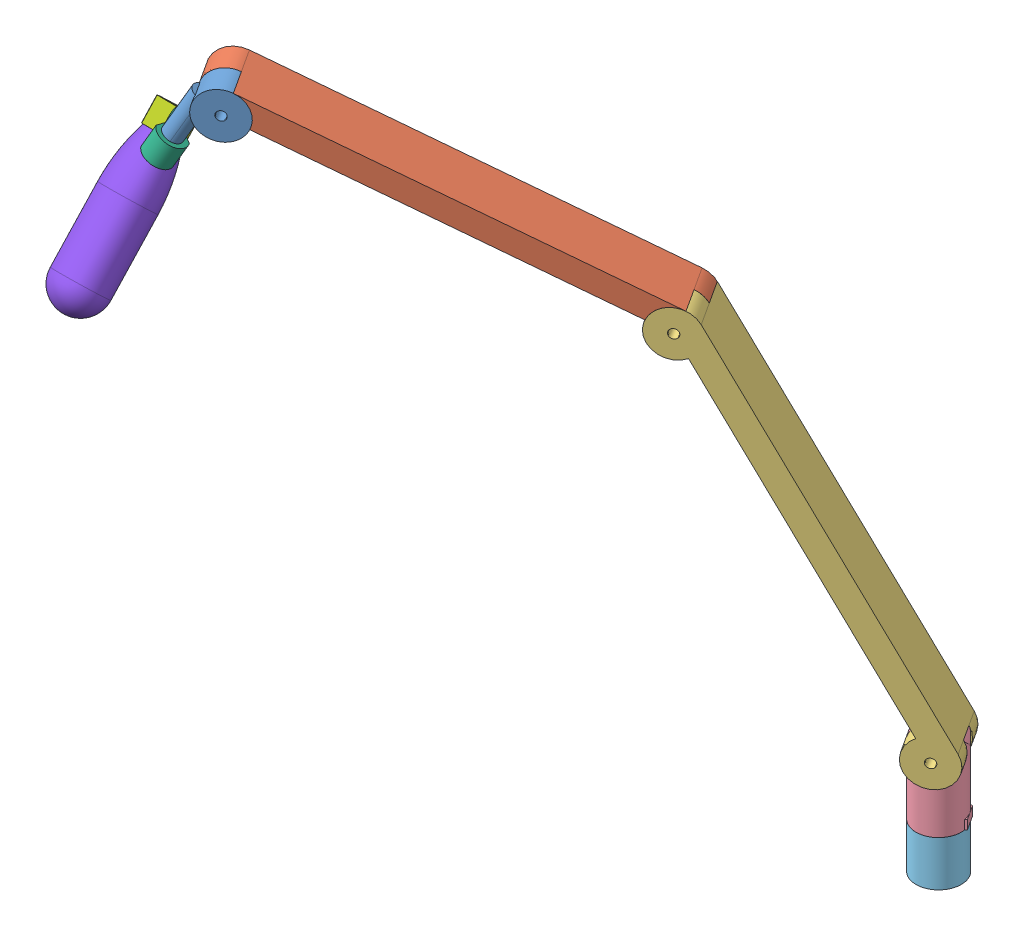
SolidWorks assembly Mic-Halter, configuration Standard. Lengths in mm.
Overall size (630.43 695.4 486.89).
8 component instances, 8 part files, 21 mates.
Components (placement in the parent):
- Mic-Arm-Kopf-1: Mic-Arm-Kopf [Standard] at (-467.7674 659.0081 383.0771) x (-0.405998 -0.875271 0.262803) z (-0.543395 0 -0.839477) size (75 55 30)
- Mic-Arm-Oberarm-1: Mic-Arm-Oberarm [Standard] at (-484.0692 659.0081 357.8928) x (-0.771647 0.393791 0.499489) z (-0.543395 0 -0.839477) size (443 50 60)
- Mic-Arm-Unterarm-1: Mic-Arm-Unterarm [Standard] at (-180.8117 504.2484 161.5937) x (-0.398411 0.880205 0.257892) z (-0.543395 0 -0.839477) size (482 50 60)
- Mic-Arm-Fuß-1: Mic-Arm-Fuß [Standard] at (-8.6981 124 50.1843) x (0 -1 0) z (-0.543395 0 -0.839477) size (99 50 50)
- Mic-Arm-Fuß-Boden-1: Mic-Arm-Fuß-Boden [Standard] at (-25 0 25) x (0 1 0) z (1 0 0) size (50 50 50)
- Mic-P120-Halter-Stativ-1: Mic-P120-Halter-Stativ [Standard] at (-527.2154 624.9172 367.9532) x (-0.579665 0.024326 -0.814492) z (-0.405998 -0.875271 0.262803) size (57.5 30 25)
- Mic-P12-Halter-Mic-1: Mic-P12-Halter-Mic [Standard] at (-574.0997 601.5346 315.0385) x (0.707701 0.484338 0.51437) z (0.002068 -0.729458 0.684022) size (71.5 38 25)
- Mic-P120-1: Mic-P120 [Standard] at (-574.048 583.2982 332.139) x (-0.877164 -0.329783 -0.349037) z (-0.480187 0.599278 0.640536) size (54 160 54)
Mates (geometry in assembly coordinates):
- Deckungsgleich1: coincident anti-aligned: plane of Mic-Arm-Oberarm-1 through (-500.3711 659.0081 332.7085) normal (0.543395 0 0.839477); plane of Mic-Arm-Kopf-1 through (-500.3711 659.0081 332.7085) normal (-0.543395 0 -0.839477)
- Konzentrisch1: concentric aligned: cylinder of Mic-Arm-Oberarm-1 through (-516.6729 659.0081 307.5242) axis (0.543395 0 0.839477) radius 5; cylinder of Mic-Arm-Kopf-1 through (-500.3711 659.0081 332.7085) axis (0.543395 0 0.839477) radius 5
- Deckungsgleich2: coincident anti-aligned: plane of Mic-Arm-Oberarm-1 through (-197.1136 504.2484 136.4094) normal (0.543395 0 0.839477); plane of Mic-Arm-Unterarm-1 through (-197.1136 504.2484 136.4094) normal (-0.543395 0 -0.839477)
- Konzentrisch2: concentric aligned: cylinder of Mic-Arm-Oberarm-1 through (-213.4154 504.2484 111.2251) axis (0.543395 0 0.839477) radius 5; cylinder of Mic-Arm-Unterarm-1 through (-213.4154 504.2484 111.2251) axis (0.543395 0 0.839477) radius 5
- Konzentrisch3: concentric aligned: cylinder of Mic-Arm-Unterarm-1 through (-41.3019 124 -0.1843) axis (0.543395 0 0.839477) radius 5; cylinder of Mic-Arm-Fuß-1 through (-41.3019 124 -0.1843) axis (0.543395 0 0.839477) radius 5
- Deckungsgleich7: coincident anti-aligned: plane of Mic-Arm-Fuß-Boden-1 through (-25 0 25) normal (0 -1 0); plane of assembly through (0 0 0) normal (0 1 0)
- Deckungsgleich8: coincident anti-aligned: plane of Mic-Arm-Fuß-Boden-1 through (-15 40 0) normal (0 0 -1); plane of assembly through (0 0 0) normal (0 0 1)
- Tangential1: tangent aligned: cylinder of Mic-Arm-Fuß-Boden-1 through (-25 50 25) axis (0 -1 0) radius 25; plane of assembly through (0 0 0) normal (1 0 0)
- Deckungsgleich9: coincident aligned: line of Mic-Arm-Fuß-1 through (-25 134 25) axis (0 -1 0); line of Mic-Arm-Fuß-Boden-1 through (-25 50 25) axis (0 -1 0)
- Deckungsgleich10: coincident anti-aligned: plane of Mic-Arm-Fuß-1 through (-62.2888 50 13.4006) normal (0 -1 0); plane of Mic-Arm-Fuß-Boden-1 through (-25 50 25) normal (0 1 0)
- LimitWinkel1: limit planar angle = 4.137913 rad anti-aligned: plane of Mic-Arm-Fuß-Boden-1 through (-15 40 0) normal (0 0 -1); plane of Mic-Arm-Fuß-1 through (1.4209 60 19.8099) normal (0.839477 0 -0.543395)
- Deckungsgleich12: coincident anti-aligned: plane of Mic-Arm-Unterarm-1 through (-30.434 124 16.6052) normal (0.543395 0 0.839477); plane of Mic-Arm-Fuß-1 through (-30.434 124 16.6052) normal (-0.543395 0 -0.839477)
- LimitWinkel2: limit planar angle = 2.64709 rad anti-aligned: plane of Mic-Arm-Unterarm-1 through (-194.9426 516.1133 99.2676) normal (0.738912 0.474594 -0.478299); plane of Mic-Arm-Fuß-1 through (1.4209 60 19.8099) normal (0.839477 0 -0.543395)
- LimitWinkel3: limit planar angle = 2.470051 rad anti-aligned: plane of Mic-Arm-Unterarm-1 through (-213.4154 504.2484 111.2251) normal (-0.738912 -0.474594 0.478299); plane of Mic-Arm-Oberarm-1 through (-516.6729 659.0081 307.5242) normal (-0.330578 -0.9192 0.213984)
- LimitWinkel4: limit planar angle = 0.100048 rad aligned: plane of Mic-Arm-Oberarm-1 through (-516.6729 659.0081 307.5242) normal (-0.330578 -0.9192 0.213984); plane of Mic-Arm-Kopf-1 through (-542.7141 629.7535 360.1172) normal (-0.405998 -0.875271 0.262803)
- Deckungsgleich13: coincident anti-aligned: plane of Mic-Arm-Kopf-1 through (-542.7141 629.7535 360.1172) normal (-0.405998 -0.875271 0.262803); plane of Mic-P120-Halter-Stativ-1 through (-527.2154 624.9172 367.9532) normal (0.405998 0.875271 -0.262803)
- Konzentrisch4: concentric anti-aligned: cylinder of Mic-Arm-Kopf-1 through (-506.9155 668.6808 354.813) axis (-0.405998 -0.875271 0.262803) radius 10; cylinder of Mic-P120-Halter-Stativ-1 through (-537.3654 603.0354 374.5233) axis (0.405998 0.875271 -0.262803) radius 15
- Deckungsgleich14: coincident anti-aligned: plane of Mic-P120-Halter-Stativ-1 through (-545.3619 601.9929 358.6974) normal (0.706509 -0.48302 -0.51724); plane of Mic-P12-Halter-Mic-1 through (-556.3525 597.825 347.5773) normal (-0.706509 0.48302 0.51724)
- Konzentrisch5: concentric anti-aligned: cylinder of Mic-P120-Halter-Stativ-1 through (-565.1955 625.3133 358.1622) axis (0.706509 -0.48302 -0.51724) radius 2.5; cylinder of Mic-P12-Halter-Mic-1 through (-529.87 601.1623 332.3002) axis (-0.706509 0.48302 0.51724) radius 2.5
- Deckungsgleich15: coincident anti-aligned: plane of Mic-P12-Halter-Mic-1 through (-574.048 583.2982 332.139) normal (0.002068 -0.729458 0.684022); plane of Mic-P120-1 through (-574.048 583.2982 332.139) normal (-0.002068 0.729458 -0.684022)
- Konzentrisch6: concentric aligned: cylinder of Mic-P12-Halter-Mic-1 through (-574.048 583.2982 332.139) axis (-0.002068 0.729458 -0.684022) radius 12.5; circle of Mic-P120-1
